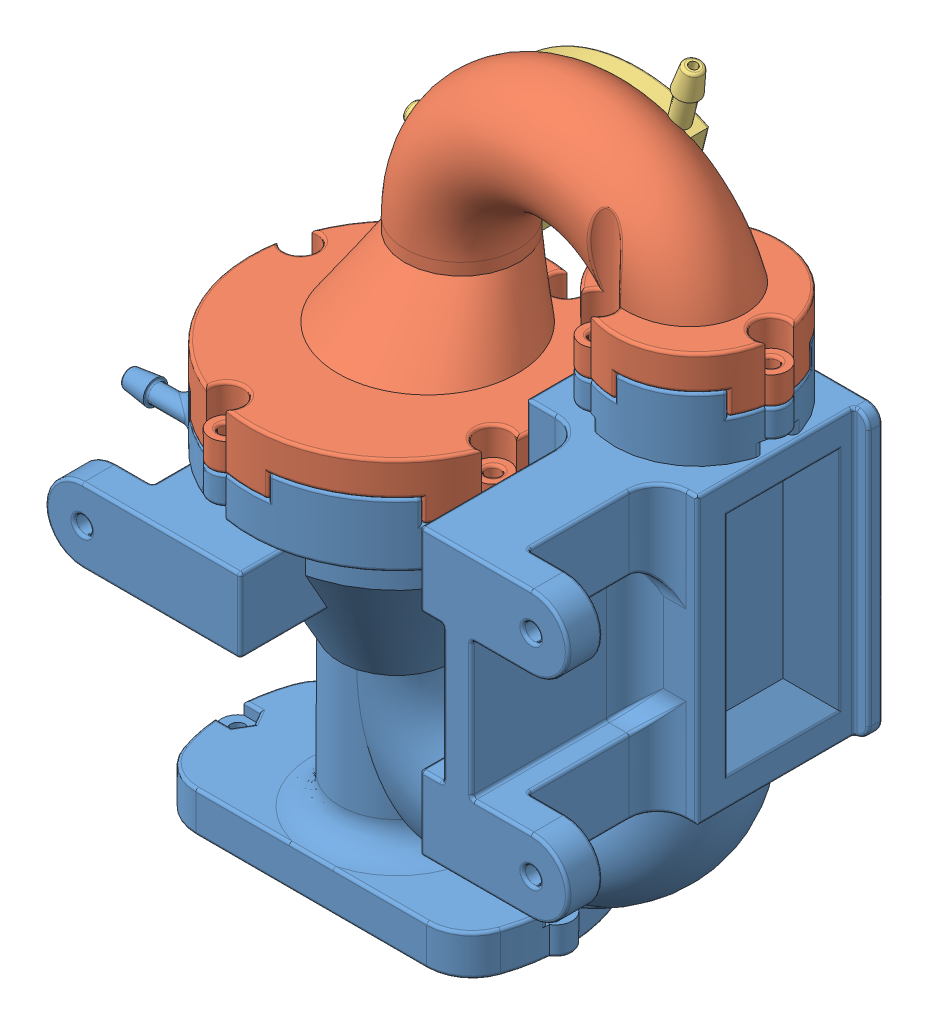
SolidWorks assembly U Tube Reference Assembly, configuration Default. Lengths in mm.
Overall size (93.6 126.87 58.74).
3 component instances, 3 part files, 13 mates.
Components (placement in the parent):
- Water Tunnel-1: Water Tunnel [Default] at origin size (93.6 95.13 58.74)
- U Tube-1: U Tube [Default] at (0 9 0) x (1 0 0) z (0 1 0) size (83.46 52.58 53.84)
- Cooling Tube Top-1: Cooling Tube Top [Default] at (0 9 8) x (1 0 0) z (0 0 -1) size (51.23 38.97 4.94)
Mates (geometry in assembly coordinates):
- Coincident1: coordinate: point of Water Tunnel-1
- InPlace1: in place: plane of Water Tunnel-1 through (0 9 0) normal (0 1 0); plane of U Tube-1 through (0 9 0) normal (0 1 0); moOrthogonalPlaneRef_w of Water Tunnel-1 through (0 9 0) normal (0 1 0); plane of U Tube-1 through (0 9 0) normal (0 0 -1); plane of Water Tunnel-1 through (0 9 0) normal (0 1 0); plane of U Tube-1 through (0 9 0) normal (1 0 0); plane of Water Tunnel-1 through (0 9 0) normal (0 1 0); unknown of U Tube-1
- Coincident2: coincident aligned: plane of ?; plane of ?
- Coincident3: coincident aligned: moOrthogonalPlaneRef_w of Water Tunnel-1 through (0 9 0) normal (0 0 -1); plane of U Tube-1 through (0 9 0) normal (0 0 -1)
- Coincident4: coincident anti-aligned: moOrthogonalPlaneRef_w of Water Tunnel-1 through (0 9 0) normal (-1 0 0); plane of U Tube-1 through (0 9 0) normal (1 0 0)
- InPlace2: in place: plane of U Tube-1 through (0 9 8) normal (0 0 -1); plane of ? through (0 0 8) normal (0 0 -1); plane of U Tube-1 through (0 9 8) normal (0 0 -1); plane of ? through (0 0 8) normal (0 1 0); plane of U Tube-1 through (0 9 8) normal (0 0 -1); plane of ? through (0 0 8) normal (-1 0 0); plane of U Tube-1 through (0 9 8) normal (0 0 -1); unknown of Cooling Tube Top-1
- Coincident2: coincident aligned: plane of ?; plane of ?
- Coincident3: coincident aligned: moOrthogonalPlaneRef_w of U Tube-1 through (0 9 8) normal (0 -1 0); plane of Part1^U Tube Reference Assembly-1 through (0 9 8) normal (0 -1 0)
- Coincident4: coincident anti-aligned: moOrthogonalPlaneRef_w of U Tube-1 through (0 9 8) normal (-1 0 0); plane of Part1^U Tube Reference Assembly-1 through (0 9 8) normal (1 0 0)
- InPlace3: in place: plane of U Tube-1 through (0 9 8) normal (0 0 -1); plane of ? through (0 0 8) normal (0 0 -1); plane of U Tube-1 through (0 9 8) normal (0 0 -1); plane of ? through (0 0 8) normal (0 1 0); plane of U Tube-1 through (0 9 8) normal (0 0 -1); plane of ? through (0 0 8) normal (-1 0 0); plane of U Tube-1 through (0 9 8) normal (0 0 -1); unknown of Cooling Tube Top-1
- Coincident5: coincident aligned: plane of ?; plane of ?
- Coincident6: coincident aligned: moOrthogonalPlaneRef_w of U Tube-1 through (0 9 8) normal (0 -1 0); plane of Copy of Part2^U Tube Reference Assembly-1 through (0 9 8) normal (0 -1 0)
- Coincident7: coincident anti-aligned: moOrthogonalPlaneRef_w of U Tube-1 through (0 9 8) normal (-1 0 0); plane of Copy of Part2^U Tube Reference Assembly-1 through (0 9 8) normal (1 0 0)
